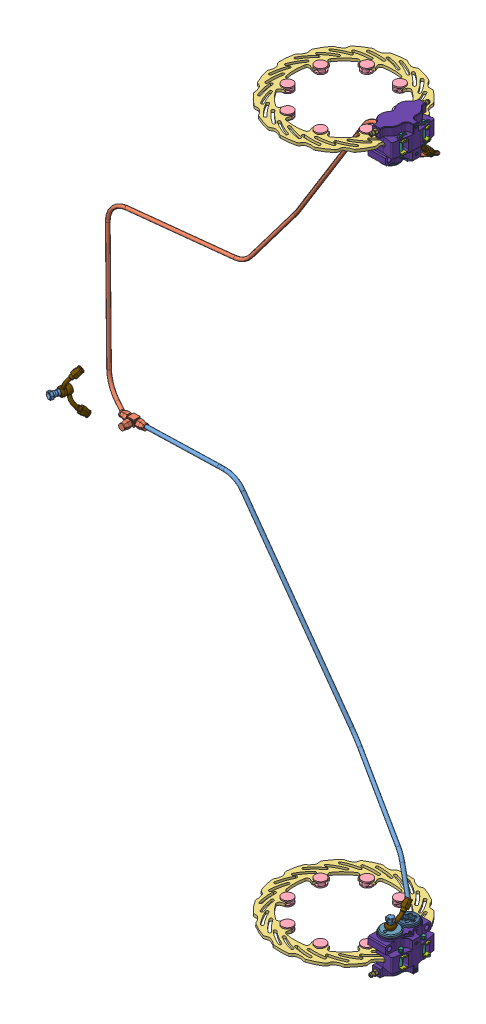
SolidWorks assembly PUTM-S-SF-BS, configuration Domyślna. Lengths in mm.
Overall size (751.18 1380.88 313.7).
104 component instances, 20 part files, 14 mates.
Components (placement in the parent):
- PUTM-S-SR-BS-Hose_FrontLeft-1: PUTM-S-SR-BS-Hose_FrontLeft [Domyślna] at (-2.0865 -0.8221 -1.1149) size (582.93 442.61 112.38)
- PUTM-S-SR-BS-Hose_Front_Right-1: PUTM-S-SR-BS-Hose_Front_Right [Domyślna] at (21.427 -0.3657 -0.9027) size (677.41 768.3 80.24)
- PUTM-S-SF-BS-ROTORS-1: PUTM-S-SF-BS-ROTORS [Domyślna] at (-0.5002 -658.8466 251.0445) x (-0.924234 0.006838 0.381764) z (0.381769 -0.00066 0.924258) size (239.96 5 240)
- PUTM-S-SR-BR-ISR_Brake Button-1: PUTM-S-SR-BR-ISR_Brake Button [Domyślna] at (-33.444 -660.7716 330.3269) x (-0.923484 0.005302 -0.383601) z (0.006572 0.999976 -0.002) size (20 20 10)
- PUTM-S-SR-BS-ISR 22-048-OB-1: PUTM-S-SR-BS-ISR 22-048-OB [Domyślna] at (104.081 -662.0338 251.1535) x (-0.000981 0.002007 0.999998) z (0.006572 0.999976 -0.002) size (110 56.69 65.5)
  - PUTM-S-SF-BS-waMygga_11-1: PUTM-S-SF-BS-waMygga_11 [Domyślna] at (-17.5609 -133.3811 -3) x (-1 0 0) z (0 1 0) size (17.93 1.25 6.8)
  - PUTM-S-SF-BS-waKlosspinne_21-1: PUTM-S-SF-BS-waKlosspinne_21 [Domyślna] at (17.8101 -133.1311 -28) x (1 0 0) z (0 1 0) size (7 38 7)
  - PUTM-S-SF-BS-waBromskloss_31-1: PUTM-S-SF-BS-waBromskloss_31 [Domyślna] at (18.7637 11.8437 8.4133) x (-0.996957 -0.077953 0) z (-0.077953 0.996957 0) size (31.91 7 47.71)
    - PUTM-S-SF-BS-waKlossplatta_301-1: PUTM-S-SF-BS-waKlossplatta_301 [Domyślna] at (35.6266 20.0867 -145.2058) size (31.91 2.5 47.71)
    - PUTM-S-SF-BS-waKlossbelgg_311-1: PUTM-S-SF-BS-waKlossbelgg_311 [Domyślna] at (35.6266 20.0867 -145.2058) size (30.8 4.5 27.94)
  - PUTM-S-SF-BS-waKolv_41-1: PUTM-S-SF-BS-waKolv_41 [Domyślna] at (-117 -100 -24) size (25 25 13)
  - PUTM-S-SF-BS-waLock upphjt_51-1: PUTM-S-SF-BS-waLock upphjt_51 [Domyślna] at (-17 0 24.5) size (34.64 33 13)
  - PUTM-S-SF-BS-waKlosspinne_21-2: PUTM-S-SF-BS-waKlosspinne_21 [Domyślna] at (60.3061 -133.1311 -28) x (1 0 0) z (0 1 0) size (7 38 7)
  - PUTM-S-SF-BS-waKula_71-1: PUTM-S-SF-BS-waKula_71 [Domyślna] at (-53.1899 32.9216 -130.9377) size (4 4 4)
  - PUTM-S-SF-BS-waLuftnippel_81-1: PUTM-S-SF-BS-waLuftnippel_81 [Domyślna] at (-55 -100 -21) x (0 -1 0) z (1 0 0) size (9.24 8 25)
  - PUTM-S-SF-BS-waKolv_41-2: PUTM-S-SF-BS-waKolv_41 [Domyślna] at (147.6777 -54.0679 24) x (-0.923728 -0.383049 0) z (0 0 -1) size (25 25 13)
  - PUTM-S-SF-BS-waTtring_101-1: PUTM-S-SF-BS-waTtring_101 [Domyślna] at (-50 134 55.9989) x (1 0 0) z (0 -1 0) size (31 3 31)
  - PUTM-S-SF-BS-waKolv_41-3: PUTM-S-SF-BS-waKolv_41 [Domyślna] at (-83 -100 -24) size (25 25 13)
  - PUTM-S-SF-BS-waBromskloss_31-2: PUTM-S-SF-BS-waBromskloss_31 [Domyślna] at (-18.7637 11.8437 -8.4133) x (0.996957 -0.077953 0) z (0.077953 0.996957 0) size (31.91 7 47.71)
    - PUTM-S-SF-BS-waKlossplatta_301-1: PUTM-S-SF-BS-waKlossplatta_301 [Domyślna] at (35.6266 20.0867 -145.2058) size (31.91 2.5 47.71)
    - PUTM-S-SF-BS-waKlossbelgg_311-1: PUTM-S-SF-BS-waKlossbelgg_311 [Domyślna] at (35.6266 20.0867 -145.2058) size (30.8 4.5 27.94)
  - PUTM-S-SF-BS-waLuftnippel_81-2: PUTM-S-SF-BS-waLuftnippel_81 [Domyślna] at (55 100 -21) x (0 1 0) z (-1 0 0) size (9.24 8 25)
  - PUTM-S-SF-BS-waKolv_41-4: PUTM-S-SF-BS-waKolv_41 [Domyślna] at (113.6777 -54.0679 24) x (-0.923728 -0.383049 0) z (0 0 -1) size (25 25 13)
  - PUTM-S-SF-BS-waTtring_101-2: PUTM-S-SF-BS-waTtring_101 [Domyślna] at (-16 -134 -56.9989) x (1 0 0) z (0 1 0) size (31 3 31)
  - PUTM-S-SF-BS-waTtring_101-3: PUTM-S-SF-BS-waTtring_101 [Domyślna] at (-16 -134 -28.5011) x (1 0 0) z (0 1 0) size (31 3 31)
  - PUTM-S-SF-BS-waLock m nippel_171-1: PUTM-S-SF-BS-waLock m nippel_171 [Domyślna] at (17 0 24.5) size (34.64 33 13)
  - PUTM-S-SF-BS-waM6_plugg_181-1: PUTM-S-SF-BS-waM6_plugg_181 [Domyślna] at (11.0714 26.7893 -134.6783) x (0.916429 -0.086532 0.390731) z (-0.389001 0.036731 0.920505) size (7.48 6 7.28)
  - PUTM-S-SF-BS-waBromskloss_31-3: PUTM-S-SF-BS-waBromskloss_31 [Domyślna] at (19.3288 11.7426 -8.4133) x (0.90799 -0.418991 0) z (0.418991 0.90799 0) size (31.91 7 47.71)
    - PUTM-S-SF-BS-waKlossplatta_301-1: PUTM-S-SF-BS-waKlossplatta_301 [Domyślna] at (35.6266 20.0867 -145.2058) size (31.91 2.5 47.71)
    - PUTM-S-SF-BS-waKlossbelgg_311-1: PUTM-S-SF-BS-waKlossbelgg_311 [Domyślna] at (35.6266 20.0867 -145.2058) size (30.8 4.5 27.94)
  - PUTM-S-SF-BS-waMygga_11-2: PUTM-S-SF-BS-waMygga_11 [Domyślna] at (17.4279 -133.3811 -28) x (1 0 0) z (0 1 0) size (17.93 1.25 6.8)
  - PUTM-S-SF-BS-waOring_evo2_211-1: PUTM-S-SF-BS-waOring_evo2_211 [Domyślna] at (-17 0 25.5) x (0 0 1) z (-1 0 0) size (1.5 30.5 30.5)
  - PUTM-S-SF-BS-waTtring_101-4: PUTM-S-SF-BS-waTtring_101 [Domyślna] at (-50 -134 -56.9989) x (1 0 0) z (0 1 0) size (31 3 31)
  - PUTM-S-SF-BS-waM6_plugg_181-2: PUTM-S-SF-BS-waM6_plugg_181 [Domyślna] at (6.511 -135.6783 9.7626) x (0.847329 0.390731 -0.35967) z (-0.35967 0.920505 0.152671) size (7.48 6 7.28)
  - PUTM-S-SF-BS-ISR 22-048-OB_241-1: PUTM-S-SF-BS-ISR 22-048-OB_241 [Domyślna] at origin size (86 50.5 61.59)
  - PUTM-S-SF-BS-waOring_evo2_211-2: PUTM-S-SF-BS-waOring_evo2_211 [Domyślna] at (17 0 25.5) x (0 0 -1) z (1 0 0) size (1.5 30.5 30.5)
  - PUTM-S-SF-BS-waKula_71-2: PUTM-S-SF-BS-waKula_71 [Domyślna] at (-53.1216 27.777 -125.5264) size (4 4 4)
  - PUTM-S-SF-BS-waM6_plugg_181-3: PUTM-S-SF-BS-waM6_plugg_181 [Domyślna] at (6.511 -136.1783 -33.4874) x (0.847329 0.390731 -0.35967) z (-0.35967 0.920505 0.152671) size (7.48 6 7.28)
  - PUTM-S-SF-BS-waBromskloss_31-4: PUTM-S-SF-BS-waBromskloss_31 [Domyślna] at (-19.3288 11.7426 8.4133) x (-0.90799 -0.418991 0) z (-0.418991 0.90799 0) size (31.91 7 47.71)
    - PUTM-S-SF-BS-waKlossplatta_301-1: PUTM-S-SF-BS-waKlossplatta_301 [Domyślna] at (35.6266 20.0867 -145.2058) size (31.91 2.5 47.71)
    - PUTM-S-SF-BS-waKlossbelgg_311-1: PUTM-S-SF-BS-waKlossbelgg_311 [Domyślna] at (35.6266 20.0867 -145.2058) size (30.8 4.5 27.94)
  - PUTM-S-SF-BS-waKula_71-3: PUTM-S-SF-BS-waKula_71 [Domyślna] at (-53.2674 32.5327 -174.1198) size (4 4 4)
- PUTM-S-SR-BS-Banjo_end_45-1: PUTM-S-SR-BS-Banjo_end_45 [Domyślna] at (104.3404 -620.0007 268.0694) x (-0.14447 -0.00103 -0.989509) z (-0.989487 0.006792 0.14446) size (52.76 29.48 16.01)
- PUTM-S-SR-BS-BANJO-BOLT-1: PUTM-S-SR-BS-BANJO-BOLT [Domyślna] at (104.3913 -612.2518 268.0539) x (-0.006572 -0.999976 0.002) z (0.58553 -0.002227 0.810647) size (35.14 13.55 12)
- PUTM-S-SR-BS-Triple-1: PUTM-S-SR-BS-Triple [Domyślna] at (-501.9994 -158.5073 137.4042) x (0 0 1) z (0 -1 0) size (29.93 46 12)
- PUTM-S-SF-BS-ROTORS-2: PUTM-S-SF-BS-ROTORS [Domyślna] at (-0.5331 663.8465 251.0545) x (-0.923484 -0.005302 -0.383601) z (-0.383581 -0.004369 0.923497) size (239.96 5 240)
- PUTM-S-SR-BR-ISR_Brake Button-2: PUTM-S-SR-BR-ISR_Brake Button [Domyślna] at (-33.3371 660.7728 330.0697) x (-0.923484 -0.005302 -0.383601) z (-0.006572 0.999976 0.002) size (20 20 10)
- PUTM-S-SR-BS-ISR 22-048-OB-2: PUTM-S-SR-BS-ISR 22-048-OB [Domyślna] at (104.0804 662.1433 251.0697) x (0.001007 -0.002007 -0.999997) z (0.006568 -0.999976 0.002014) size (110 56.69 65.5)
  - PUTM-S-SF-BS-waMygga_11-1: PUTM-S-SF-BS-waMygga_11 [Domyślna] at (-17.5609 -133.3811 -3) x (-1 0 0) z (0 1 0) size (17.93 1.25 6.8)
  - PUTM-S-SF-BS-waKlosspinne_21-1: PUTM-S-SF-BS-waKlosspinne_21 [Domyślna] at (17.8101 -133.1311 -28) x (1 0 0) z (0 1 0) size (7 38 7)
  - PUTM-S-SF-BS-waBromskloss_31-1: PUTM-S-SF-BS-waBromskloss_31 [Domyślna] at (18.7637 11.8437 8.4133) x (-0.996957 -0.077953 0) z (-0.077953 0.996957 0) size (31.91 7 47.71)
    - PUTM-S-SF-BS-waKlossplatta_301-1: PUTM-S-SF-BS-waKlossplatta_301 [Domyślna] at (35.6266 20.0867 -145.2058) size (31.91 2.5 47.71)
    - PUTM-S-SF-BS-waKlossbelgg_311-1: PUTM-S-SF-BS-waKlossbelgg_311 [Domyślna] at (35.6266 20.0867 -145.2058) size (30.8 4.5 27.94)
  - PUTM-S-SF-BS-waKolv_41-1: PUTM-S-SF-BS-waKolv_41 [Domyślna] at (-117 -100 -24) size (25 25 13)
  - PUTM-S-SF-BS-waLock upphjt_51-1: PUTM-S-SF-BS-waLock upphjt_51 [Domyślna] at (-17 0 24.5) size (34.64 33 13)
  - PUTM-S-SF-BS-waKlosspinne_21-2: PUTM-S-SF-BS-waKlosspinne_21 [Domyślna] at (60.3061 -133.1311 -28) x (1 0 0) z (0 1 0) size (7 38 7)
  - PUTM-S-SF-BS-waKula_71-1: PUTM-S-SF-BS-waKula_71 [Domyślna] at (-53.1899 32.9216 -130.9377) size (4 4 4)
  - PUTM-S-SF-BS-waLuftnippel_81-1: PUTM-S-SF-BS-waLuftnippel_81 [Domyślna] at (-55 -100 -21) x (0 -1 0) z (1 0 0) size (9.24 8 25)
  - PUTM-S-SF-BS-waKolv_41-2: PUTM-S-SF-BS-waKolv_41 [Domyślna] at (147.6777 -54.0679 24) x (-0.923728 -0.383049 0) z (0 0 -1) size (25 25 13)
  - PUTM-S-SF-BS-waTtring_101-1: PUTM-S-SF-BS-waTtring_101 [Domyślna] at (-50 134 55.9989) x (1 0 0) z (0 -1 0) size (31 3 31)
  - PUTM-S-SF-BS-waKolv_41-3: PUTM-S-SF-BS-waKolv_41 [Domyślna] at (-83 -100 -24) size (25 25 13)
  - PUTM-S-SF-BS-waBromskloss_31-2: PUTM-S-SF-BS-waBromskloss_31 [Domyślna] at (-18.7637 11.8437 -8.4133) x (0.996957 -0.077953 0) z (0.077953 0.996957 0) size (31.91 7 47.71)
    - PUTM-S-SF-BS-waKlossplatta_301-1: PUTM-S-SF-BS-waKlossplatta_301 [Domyślna] at (35.6266 20.0867 -145.2058) size (31.91 2.5 47.71)
    - PUTM-S-SF-BS-waKlossbelgg_311-1: PUTM-S-SF-BS-waKlossbelgg_311 [Domyślna] at (35.6266 20.0867 -145.2058) size (30.8 4.5 27.94)
  - PUTM-S-SF-BS-waLuftnippel_81-2: PUTM-S-SF-BS-waLuftnippel_81 [Domyślna] at (55 100 -21) x (0 1 0) z (-1 0 0) size (9.24 8 25)
  - PUTM-S-SF-BS-waKolv_41-4: PUTM-S-SF-BS-waKolv_41 [Domyślna] at (113.6777 -54.0679 24) x (-0.923728 -0.383049 0) z (0 0 -1) size (25 25 13)
  - PUTM-S-SF-BS-waTtring_101-2: PUTM-S-SF-BS-waTtring_101 [Domyślna] at (-16 -134 -56.9989) x (1 0 0) z (0 1 0) size (31 3 31)
  - PUTM-S-SF-BS-waTtring_101-3: PUTM-S-SF-BS-waTtring_101 [Domyślna] at (-16 -134 -28.5011) x (1 0 0) z (0 1 0) size (31 3 31)
  - PUTM-S-SF-BS-waLock m nippel_171-1: PUTM-S-SF-BS-waLock m nippel_171 [Domyślna] at (17 0 24.5) size (34.64 33 13)
  - PUTM-S-SF-BS-waM6_plugg_181-1: PUTM-S-SF-BS-waM6_plugg_181 [Domyślna] at (11.0714 26.7893 -134.6783) x (0.916429 -0.086532 0.390731) z (-0.389001 0.036731 0.920505) size (7.48 6 7.28)
  - PUTM-S-SF-BS-waBromskloss_31-3: PUTM-S-SF-BS-waBromskloss_31 [Domyślna] at (19.3288 11.7426 -8.4133) x (0.90799 -0.418991 0) z (0.418991 0.90799 0) size (31.91 7 47.71)
    - PUTM-S-SF-BS-waKlossplatta_301-1: PUTM-S-SF-BS-waKlossplatta_301 [Domyślna] at (35.6266 20.0867 -145.2058) size (31.91 2.5 47.71)
    - PUTM-S-SF-BS-waKlossbelgg_311-1: PUTM-S-SF-BS-waKlossbelgg_311 [Domyślna] at (35.6266 20.0867 -145.2058) size (30.8 4.5 27.94)
  - PUTM-S-SF-BS-waMygga_11-2: PUTM-S-SF-BS-waMygga_11 [Domyślna] at (17.4279 -133.3811 -28) x (1 0 0) z (0 1 0) size (17.93 1.25 6.8)
  - PUTM-S-SF-BS-waOring_evo2_211-1: PUTM-S-SF-BS-waOring_evo2_211 [Domyślna] at (-17 0 25.5) x (0 0 1) z (-1 0 0) size (1.5 30.5 30.5)
  - PUTM-S-SF-BS-waTtring_101-4: PUTM-S-SF-BS-waTtring_101 [Domyślna] at (-50 -134 -56.9989) x (1 0 0) z (0 1 0) size (31 3 31)
  - PUTM-S-SF-BS-waM6_plugg_181-2: PUTM-S-SF-BS-waM6_plugg_181 [Domyślna] at (6.511 -135.6783 9.7626) x (0.847329 0.390731 -0.35967) z (-0.35967 0.920505 0.152671) size (7.48 6 7.28)
  - PUTM-S-SF-BS-ISR 22-048-OB_241-1: PUTM-S-SF-BS-ISR 22-048-OB_241 [Domyślna] at origin size (86 50.5 61.59)
  - PUTM-S-SF-BS-waOring_evo2_211-2: PUTM-S-SF-BS-waOring_evo2_211 [Domyślna] at (17 0 25.5) x (0 0 -1) z (1 0 0) size (1.5 30.5 30.5)
  - PUTM-S-SF-BS-waKula_71-2: PUTM-S-SF-BS-waKula_71 [Domyślna] at (-53.1216 27.777 -125.5264) size (4 4 4)
  - PUTM-S-SF-BS-waM6_plugg_181-3: PUTM-S-SF-BS-waM6_plugg_181 [Domyślna] at (6.511 -136.1783 -33.4874) x (0.847329 0.390731 -0.35967) z (-0.35967 0.920505 0.152671) size (7.48 6 7.28)
  - PUTM-S-SF-BS-waBromskloss_31-4: PUTM-S-SF-BS-waBromskloss_31 [Domyślna] at (-19.3288 11.7426 8.4133) x (-0.90799 -0.418991 0) z (-0.418991 0.90799 0) size (31.91 7 47.71)
    - PUTM-S-SF-BS-waKlossplatta_301-1: PUTM-S-SF-BS-waKlossplatta_301 [Domyślna] at (35.6266 20.0867 -145.2058) size (31.91 2.5 47.71)
    - PUTM-S-SF-BS-waKlossbelgg_311-1: PUTM-S-SF-BS-waKlossbelgg_311 [Domyślna] at (35.6266 20.0867 -145.2058) size (30.8 4.5 27.94)
  - PUTM-S-SF-BS-waKula_71-3: PUTM-S-SF-BS-waKula_71 [Domyślna] at (-53.2674 32.5327 -174.1198) size (4 4 4)
- PUTM-S-SR-BS-BANJO-BOLT-3: PUTM-S-SR-BS-BANJO-BOLT [Domyślna] at (104.4089 614.7093 234.1652) x (-0.006568 0.999976 -0.002014) z (-0.045043 0.001716 0.998984) size (35.14 13.55 12)
- PUTM-S-SR-BS-Banjo_end_45-4: PUTM-S-SR-BS-Banjo_end_45 [Domyślna] at (104.3734 620.1102 234.1543) x (0.055221 -0.001648 -0.998473) z (0.998453 0.006669 0.055208) size (52.76 29.48 16.01)
- PUTM-S-SR-BR-ISR_Brake Button-3: PUTM-S-SR-BR-ISR_Brake Button [Domyślna] at (32.2577 -661.2033 330.3922) x (-0.924234 0.006838 0.381764) z (0.006572 0.999976 -0.002) size (20 20 10)
- PUTM-S-SR-BR-ISR_Brake Button-4: PUTM-S-SR-BR-ISR_Brake Button [Domyślna] at (78.7613 -661.6017 283.9794) x (-0.383581 0.004369 0.923497) z (0.006572 0.999976 -0.002) size (20 20 10)
- PUTM-S-SR-BR-ISR_Brake Button-5: PUTM-S-SR-BR-ISR_Brake Button [Domyślna] at (78.8258 -661.7336 218.2765) x (0.381769 -0.00066 0.924258) z (0.006572 0.999976 -0.002) size (20 20 10)
- PUTM-S-SR-BR-ISR_Brake Button-6: PUTM-S-SR-BR-ISR_Brake Button [Domyślna] at (32.4133 -661.5216 171.7713) x (0.923484 -0.005302 0.383601) z (0.006572 0.999976 -0.002) size (20 20 10)
- PUTM-S-SR-BR-ISR_Brake Button-7: PUTM-S-SR-BR-ISR_Brake Button [Domyślna] at (-33.2884 -661.0899 171.706) x (0.924234 -0.006838 -0.381764) z (0.006572 0.999976 -0.002) size (20 20 10)
- PUTM-S-SR-BR-ISR_Brake Button-8: PUTM-S-SR-BR-ISR_Brake Button [Domyślna] at (-79.792 -660.6914 218.1188) x (0.383581 -0.004369 -0.923497) z (0.006572 0.999976 -0.002) size (20 20 10)
- PUTM-S-SR-BR-ISR_Brake Button-9: PUTM-S-SR-BR-ISR_Brake Button [Domyślna] at (-79.8565 -660.5596 283.8217) x (-0.381769 0.00066 -0.924258) z (0.006572 0.999976 -0.002) size (20 20 10)
- PUTM-S-SR-BR-ISR_Brake Button-10: PUTM-S-SR-BR-ISR_Brake Button [Domyślna] at (32.1514 661.2031 330.1348) x (-0.924234 -0.006838 0.381764) z (-0.006572 0.999976 0.002) size (20 20 10)
- PUTM-S-SR-BR-ISR_Brake Button-11: PUTM-S-SR-BR-ISR_Brake Button [Domyślna] at (78.5042 661.6003 283.8726) x (-0.383581 -0.004369 0.923497) z (-0.006572 0.999976 0.002) size (20 20 10)
- PUTM-S-SR-BR-ISR_Brake Button-12: PUTM-S-SR-BR-ISR_Brake Button [Domyślna] at (78.5684 661.7317 218.3828) x (0.381769 0.00066 0.924258) z (-0.006572 0.999976 0.002) size (20 20 10)
- PUTM-S-SR-BR-ISR_Brake Button-13: PUTM-S-SR-BR-ISR_Brake Button [Domyślna] at (32.3064 661.5204 172.0285) x (0.923484 0.005302 0.383601) z (-0.006572 0.999976 0.002) size (20 20 10)
- PUTM-S-SR-BR-ISR_Brake Button-14: PUTM-S-SR-BR-ISR_Brake Button [Domyślna] at (-33.1821 661.0901 171.9634) x (0.924234 0.006838 -0.381764) z (-0.006572 0.999976 0.002) size (20 20 10)
- PUTM-S-SR-BR-ISR_Brake Button-15: PUTM-S-SR-BR-ISR_Brake Button [Domyślna] at (-79.5348 660.6929 218.2256) x (0.383581 0.004369 -0.923497) z (-0.006572 0.999976 0.002) size (20 20 10)
- PUTM-S-SR-BR-ISR_Brake Button-16: PUTM-S-SR-BR-ISR_Brake Button [Domyślna] at (-79.5991 660.5615 283.7154) x (-0.381769 -0.00066 -0.924258) z (-0.006572 0.999976 0.002) size (20 20 10)
- PUTM-S-SR-BS-BANJO-BOLT-4: PUTM-S-SR-BS-BANJO-BOLT [Domyślna] at (-584.5203 -129 213.7953) x (0.260065 0 -0.965591) z (-0.636263 -0.752199 -0.171366) size (35.14 13.55 12)
- PUTM-S-SR-BS-Banjo_end_45-5: PUTM-S-SR-BS-Banjo_end_45 [Domyślna] at (-580.5778 -129 199.1571) x (0.347034 0.933183 0.093467) z (0.901074 -0.3594 0.242688) size (52.76 29.48 16.01)
- PUTM-S-SR-BS-Banjo_end_45-7: PUTM-S-SR-BS-Banjo_end_45 [Domyślna] at (-578.2372 -129 190.4668) x (0.416859 -0.902011 0.112274) z (-0.870973 -0.431714 -0.234581) size (52.76 29.48 16.01)
Mates (geometry in assembly coordinates):
- Wspólnie71: coincident anti-aligned: plane of PUTM-S-SF-BS-ROTORS-1 through (-38.1554 -663.4441 328.5978) normal (0.923484 -0.005302 0.383601); plane of PUTM-S-SR-BR-ISR_Brake Button-1 through (-34.2078 -658.0888 319.1685) normal (-0.923484 0.005302 -0.383601)
- Wspólnie72: coincident anti-aligned: plane of PUTM-S-SF-BS-ROTORS-1 through (72.4374 -664.1481 340.0148) normal (-0.006572 -0.999976 0.002); plane of PUTM-S-SR-BR-ISR_Brake Button-1 through (-33.4617 -663.4715 330.3323) normal (0.006572 0.999976 -0.002)
- Odległość8: distance = 1.5 mm anti-aligned: plane of PUTM-S-SR-BS-ISR 22-048-OB-1/PUTM-S-SF-BS-waBromskloss_31-1/PUTM-S-SF-BS-waKlossbelgg_311-1 through (117.544 -658.0942 265.1683) normal (-0.006572 -0.999976 0.002); plane of PUTM-S-SF-BS-ROTORS-1 through (72.4703 -659.1483 340.0048) normal (0.006572 0.999976 -0.002)
- Wspólnie73: coincident anti-aligned: plane of PUTM-S-SR-BS-ISR 22-048-OB-1/PUTM-S-SF-BS-waLock m nippel_171-1 through (104.3108 -624.5006 268.0784) normal (0.006572 0.999976 -0.002); plane of PUTM-S-SR-BS-Banjo_end_45-1 through (104.3108 -624.5006 268.0784) normal (-0.006572 -0.999976 0.002)
- Koncentryczne35: concentric aligned: circle of PUTM-S-SR-BS-ISR 22-048-OB-1/PUTM-S-SF-BS-waLock m nippel_171-1; circle of PUTM-S-SR-BS-Banjo_end_45-1
- Koncentryczne36: concentric aligned: cylinder of PUTM-S-SR-BS-Banjo_end_45-1 through (104.3107 -624.5241 268.0785) axis (0.006572 0.999976 -0.002) radius 5.1; cylinder of PUTM-S-SR-BS-BANJO-BOLT-1 through (104.3913 -612.2518 268.0539) axis (0.006572 0.999976 -0.002) radius 4.7625
- Wspólnie76: coincident anti-aligned: plane of PUTM-S-SF-BS-ROTORS-2 through (-11.8376 663.5432 365.557) normal (-0.006572 0.999976 0.002); plane of PUTM-S-SR-BR-ISR_Brake Button-2 through (-31.437 663.4946 325.4576) normal (0.006572 -0.999976 -0.002)
- Wspólnie77: coincident anti-aligned: plane of PUTM-S-SF-BS-ROTORS-2 through (-38.1225 658.4442 328.5878) normal (0.923484 0.005302 0.383601); plane of PUTM-S-SR-BR-ISR_Brake Button-2 through (-34.1365 663.4899 318.9221) normal (-0.923484 -0.005302 -0.383601)
- Koncentryczne41: concentric aligned: circle of PUTM-S-SR-BS-ISR 22-048-OB-2/PUTM-S-SF-BS-waLock m nippel_171-1; cylinder of PUTM-S-SR-BS-BANJO-BOLT-3 through (104.4089 614.7093 234.1652) axis (0.006568 -0.999976 0.002014) radius 4.7625
- Wspólnie78: coincident anti-aligned: plane of PUTM-S-SR-BS-ISR 22-048-OB-2/PUTM-S-SF-BS-waLock m nippel_171-1 through (104.3438 624.6101 234.1452) normal (0.006568 -0.999976 0.002014); plane of PUTM-S-SR-BS-Banjo_end_45-4 through (104.3438 624.6101 234.1452) normal (-0.006568 0.999976 -0.002014)
- Koncentryczne42: concentric aligned: cylinder of PUTM-S-SR-BS-Banjo_end_45-4 through (104.3437 624.6336 234.1452) axis (0.006568 -0.999976 0.002014) radius 5.1; cylinder of PUTM-S-SR-BS-BANJO-BOLT-3 through (104.4089 614.7093 234.1652) axis (0.006568 -0.999976 0.002014) radius 4.7625
- Koncentryczne50: concentric anti-aligned: cylinder of PUTM-S-SR-BS-BANJO-BOLT-4 through (-584.5203 -129 213.7953) axis (-0.260065 0 0.965591) radius 4.7625; cylinder of PUTM-S-SR-BS-Banjo_end_45-5 through (-581.7542 -129 203.5249) axis (0.260065 0 -0.965591) radius 5.1
- Koncentryczne51: concentric anti-aligned: cylinder of PUTM-S-SR-BS-BANJO-BOLT-4 through (-584.5203 -129 213.7953) axis (-0.260065 0 0.965591) radius 4.7625; cylinder of PUTM-S-SR-BS-Banjo_end_45-7 through (-579.4136 -129 194.8346) axis (0.260065 0 -0.965591) radius 5.1
- Wspólnie82: coincident anti-aligned: plane of PUTM-S-SR-BS-Banjo_end_45-7 through (-579.4075 -129 194.8119) normal (-0.260065 0 0.965591); plane of PUTM-S-SR-BS-Banjo_end_45-5 through (-579.4075 -129 194.8119) normal (0.260065 0 -0.965591)
